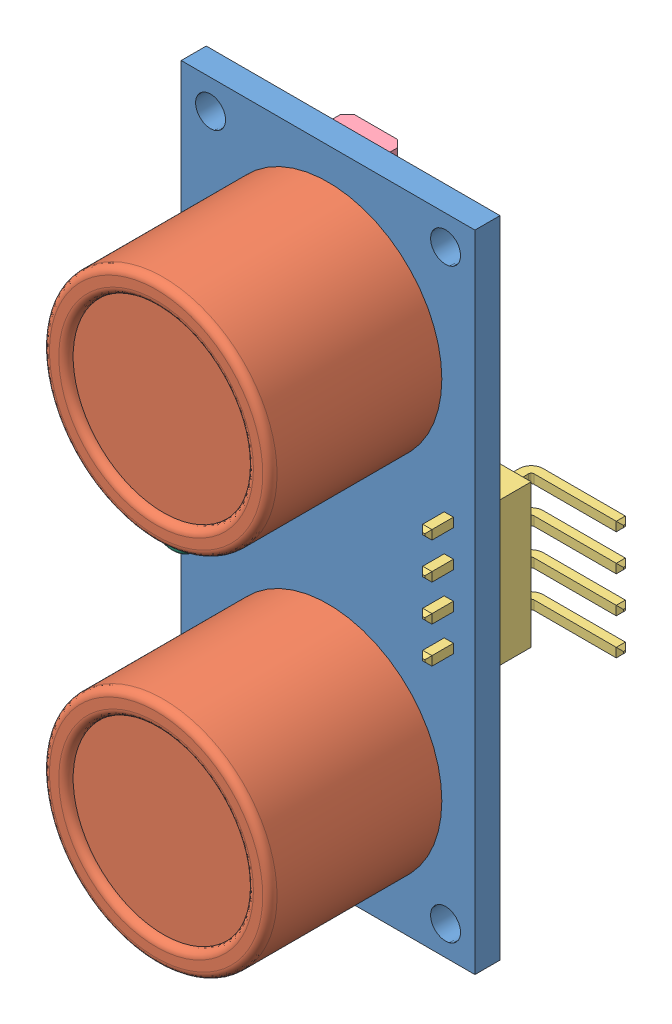
SolidWorks assembly HC-SR04 Ping Sensor, configuration Default. Lengths in mm.
Overall size (25.18 45 18.07).
14 component instances, 6 part files, 46 mates.
Components (placement in the parent):
- PCB-1: PCB [Default] at origin size (20.5 45 1.75)
- Transducer-1: Transducer [Default] at (0 -13.16 13.25) x (1 0 0) z (0 -1 0) size (15.88 12 15.88)
- Transducer-2: Transducer [Default] at (0 12.34 13.25) x (1 0 0) z (0 -1 0) size (15.88 12 15.88)
- 3 Pin Header 90 Degree-1: 3 Pin Header 90 Degree [Default] at (8.4275 0 -1.25) x (-1 0 0) z (0 -1 0) size (8 7.82 10)
- 14 Pin SMT-1: 14 Pin SMT [Default] at (-0.35 -18.5 -0.85) x (0 -1 0) z (1 0 0) size (6 1.6 8.8)
- 14 Pin SMT-2: 14 Pin SMT [Default] at (0 -0.3826 -0.85) x (1 0 0) z (0 1 0) size (6 1.6 8.8)
- 14 Pin SMT-3: 14 Pin SMT [Default] at (0 17.5274 -0.85) x (1 0 0) z (0 1 0) size (6 1.6 8.8)
- Cap1 SMT-1: Cap1 SMT [Default] at (-1.755 7.4774 -0.9689) x (0 1 0) z (-1 0 0) size (4.5 1.84 1.75)
- Cap1 SMT-2: Cap1 SMT [Default] at (6.835 7.4774 -0.9689) x (0 1 0) z (-1 0 0) size (4.5 1.84 1.75)
- Cap1 SMT-3: Cap1 SMT [Default] at (-6.835 7.4774 -0.9689) x (0 1 0) z (-1 0 0) size (4.5 1.84 1.75)
- Cap1 SMT-4: Cap1 SMT [Default] at (4.295 7.4774 -0.9689) x (0 1 0) z (-1 0 0) size (4.5 1.84 1.75)
- Cap1 SMT-5: Cap1 SMT [Default] at (1.755 7.4774 -0.9689) x (0 1 0) z (-1 0 0) size (4.5 1.84 1.75)
- Cap1 SMT-6: Cap1 SMT [Default] at (-4.295 7.4774 -0.9689) x (0 1 0) z (-1 0 0) size (4.5 1.84 1.75)
- HC-SR04 Crystal-1: HC-SR04 Crystal [Default] at (-8.3 0 1.75) x (0 -1 0) z (0 0 1) size (10 3.5 2.7)
Mates (geometry in assembly coordinates):
- Coincident1: coincident anti-aligned: plane of PCB-1 through (-10.25 -22.5 1.75) normal (0 0 1); plane of Transducer-2 through (0 12.34 1.75) normal (0 0 -1)
- Coincident2: coincident anti-aligned: plane of PCB-1 through (-10.25 -22.5 1.75) normal (0 0 1); plane of Transducer-1 through (0 -13.16 1.75) normal (0 0 -1)
- Coincident3: coincident aligned: plane of PCB-1 through (0 0 0) normal (1 0 0); plane of Transducer-1
- Coincident4: coincident aligned: plane of PCB-1 through (0 0 0) normal (1 0 0); plane of Transducer-2
- Distance2: distance = 9.34 mm: plane of PCB-1 through (-10.25 -22.5 1.75) normal (0 -1 0); point of Transducer-1
- Distance3: distance = 10.16 mm: plane of PCB-1 through (-10.25 22.5 1.75) normal (0 1 0); point of Transducer-2
- Coincident8: coincident anti-aligned: plane of PCB-1 through (0 0 0) normal (0 1 0); plane of 3 Pin Header 90 Degree-1 through (8.4275 0 -1.25) normal (0 -1 0)
- Coincident9: coincident anti-aligned: plane of PCB-1 through (-10.25 -22.5 0) normal (0 0 -1); plane of 14 Pin SMT-1 through (-0.6 -21.5 0) normal (0 0 1)
- Coincident10: coincident anti-aligned: plane of PCB-1 through (-10.25 -22.5 0) normal (0 0 -1); plane of 14 Pin SMT-2 through (3 -0.6326 0) normal (0 0 1)
- Coincident11: coincident anti-aligned: plane of PCB-1 through (-10.25 -22.5 0) normal (0 0 -1); plane of 14 Pin SMT-3 through (3 18.5274 0) normal (0 0 1)
- Coincident13: coincident aligned: plane of PCB-1 through (0 0 0) normal (1 0 0); plane of 14 Pin SMT-2
- Coincident14: coincident aligned: plane of PCB-1 through (0 0 0) normal (1 0 0); plane of 14 Pin SMT-3
- Distance6: distance = 9.11 mm anti-aligned: plane of 14 Pin SMT-2 through (-2 4.0174 -1.6) normal (0 1 0); plane of 14 Pin SMT-3 through (-2 13.1274 -1.6) normal (0 -1 0)
- Coincident15: coincident anti-aligned: plane of PCB-1 through (-10.25 -22.5 0) normal (0 0 -1); plane of Cap1 SMT-1 through (-2.005 9.7274 0) normal (0 0 1)
- Coincident16: coincident anti-aligned: plane of PCB-1 through (-10.25 -22.5 0) normal (0 0 -1); plane of Cap1 SMT-2 through (6.585 9.7274 0) normal (0 0 1)
- Coincident17: coincident anti-aligned: plane of PCB-1 through (-10.25 -22.5 0) normal (0 0 -1); plane of Cap1 SMT-3 through (-7.085 9.7274 0) normal (0 0 1)
- Coincident18: coincident anti-aligned: plane of PCB-1 through (-10.25 -22.5 0) normal (0 0 -1); plane of Cap1 SMT-4 through (4.045 9.7274 0) normal (0 0 1)
- Coincident19: coincident anti-aligned: plane of PCB-1 through (-10.25 -22.5 0) normal (0 0 -1); plane of Cap1 SMT-5 through (1.505 9.7274 0) normal (0 0 1)
- Coincident20: coincident anti-aligned: plane of PCB-1 through (-10.25 -22.5 0) normal (0 0 -1); plane of Cap1 SMT-6 through (-4.545 9.7274 0) normal (0 0 1)
- Parallel1: parallel aligned: plane of Cap1 SMT-4 through (3.42 5.7274 -1.8439) normal (0 -1 0); plane of Cap1 SMT-5 through (0.88 5.7274 -1.8439) normal (0 -1 0)
- Parallel2: parallel aligned: plane of Cap1 SMT-2 through (5.96 5.7274 -1.8439) normal (0 -1 0); plane of Cap1 SMT-4 through (3.42 5.7274 -1.8439) normal (0 -1 0)
- Parallel3: parallel aligned: plane of PCB-1 through (-10.25 -22.5 1.75) normal (0 -1 0); plane of Cap1 SMT-2 through (5.96 5.7274 -1.8439) normal (0 -1 0)
- Distance7: distance = 0.79 mm anti-aligned: plane of Cap1 SMT-2 through (5.96 5.7274 -1.8439) normal (-1 0 0); plane of Cap1 SMT-4 through (5.17 5.7274 -1.8439) normal (1 0 0)
- Distance8: distance = 0.79 mm anti-aligned: plane of Cap1 SMT-4 through (3.42 5.7274 -1.8439) normal (-1 0 0); plane of Cap1 SMT-5 through (2.63 5.7274 -1.8439) normal (1 0 0)
- Distance9: distance = 2.54 mm aligned: plane of PCB-1 through (10.25 22.5 1.75) normal (1 0 0); plane of Cap1 SMT-2 through (7.71 5.7274 -1.8439) normal (1 0 0)
- Coincident21: coincident aligned: plane of Cap1 SMT-4 through (3.42 9.2274 -0.0939) normal (0 1 0); plane of Cap1 SMT-5 through (0.88 9.2274 -0.0939) normal (0 1 0)
- Coincident22: coincident aligned: plane of Cap1 SMT-2 through (5.96 9.2274 -0.0939) normal (0 1 0); plane of Cap1 SMT-4 through (3.42 9.2274 -0.0939) normal (0 1 0)
- Parallel4: parallel aligned: plane of Cap1 SMT-3 through (-7.71 5.7274 -1.8439) normal (0 -1 0); plane of Cap1 SMT-6 through (-5.17 5.7274 -1.8439) normal (0 -1 0)
- Parallel5: parallel aligned: plane of Cap1 SMT-1 through (-2.63 5.7274 -1.8439) normal (0 -1 0); plane of Cap1 SMT-6 through (-5.17 5.7274 -1.8439) normal (0 -1 0)
- Distance11: distance = 0.79 mm anti-aligned: plane of Cap1 SMT-1 through (-2.63 5.7274 -1.8439) normal (-1 0 0); plane of Cap1 SMT-6 through (-3.42 5.7274 -1.8439) normal (1 0 0)
- Distance12: distance = 0.79 mm anti-aligned: plane of Cap1 SMT-3 through (-5.96 5.7274 -1.8439) normal (1 0 0); plane of Cap1 SMT-6 through (-5.17 5.7274 -1.8439) normal (-1 0 0)
- Coincident23: coincident aligned: plane of Cap1 SMT-3 through (-7.71 9.2274 -0.0939) normal (0 1 0); plane of Cap1 SMT-6 through (-5.17 9.2274 -0.0939) normal (0 1 0)
- Coincident24: coincident aligned: plane of Cap1 SMT-1 through (-2.63 9.2274 -0.0939) normal (0 1 0); plane of Cap1 SMT-6 through (-5.17 9.2274 -0.0939) normal (0 1 0)
- Parallel6: parallel aligned: plane of PCB-1 through (-10.25 -22.5 1.75) normal (0 -1 0); plane of Cap1 SMT-3 through (-7.71 5.7274 -1.8439) normal (0 -1 0)
- Distance13: distance = 2.54 mm aligned: plane of PCB-1 through (-10.25 22.5 1.75) normal (-1 0 0); plane of Cap1 SMT-3 through (-7.71 5.7274 -1.8439) normal (-1 0 0)
- Coincident25: coincident aligned: plane of Cap1 SMT-1 through (-2.63 9.2274 -0.0939) normal (0 1 0); plane of Cap1 SMT-5 through (0.88 9.2274 -0.0939) normal (0 1 0)
- Distance15: distance = 1.71 mm anti-aligned: plane of 14 Pin SMT-2 through (-2 4.0174 -1.6) normal (0 1 0); plane of Cap1 SMT-5 through (0.88 5.7274 -1.8439) normal (0 -1 0)
- Coincident26: coincident anti-aligned: plane of PCB-1 through (-10.25 -22.5 0) normal (0 0 -1); plane of 3 Pin Header 90 Degree-1 through (9.9275 -5 0) normal (0 0 1)
- Distance16: distance = 1.5 mm aligned: plane of 3 Pin Header 90 Degree-1 through (8.75 4.4 -2.5) normal (1 0 0); plane of PCB-1 through (10.25 22.5 1.75) normal (1 0 0)
- Parallel7: parallel anti-aligned: plane of PCB-1 through (-10.25 22.5 1.75) normal (-1 0 0); plane of 14 Pin SMT-1 through (4.05 -16.5 -1.6) normal (1 0 0)
- Distance17: distance = 5.5 mm aligned: plane of 14 Pin SMT-1 through (-4.75 -16.5 -1.6) normal (-1 0 0); plane of PCB-1 through (-10.25 22.5 1.75) normal (-1 0 0)
- Distance18: distance = 2 mm aligned: plane of 14 Pin SMT-1 through (4.05 -20.5 -0.1) normal (0 -1 0); plane of PCB-1 through (-10.25 -22.5 1.75) normal (0 -1 0)
- Distance19: distance = 0.5726 mm aligned: plane of 14 Pin SMT-3 through (-2 21.9274 -1.6) normal (0 1 0); plane of PCB-1 through (-10.25 22.5 1.75) normal (0 1 0)
- Distance20: distance = 0.2 mm aligned: plane of PCB-1 through (-10.25 22.5 1.75) normal (-1 0 0); plane of HC-SR04 Crystal-1 through (-10.05 3.25 4.45) normal (-1 0 0)
- Coincident36: coincident anti-aligned: plane of PCB-1 through (-10.25 -22.5 1.75) normal (0 0 1); plane of HC-SR04 Crystal-1 through (-8.3 3.25 1.75) normal (0 0 -1)
- Coincident37: coincident anti-aligned: plane of HC-SR04 Crystal-1; plane of assembly through (0 0 0) normal (0 1 0)
